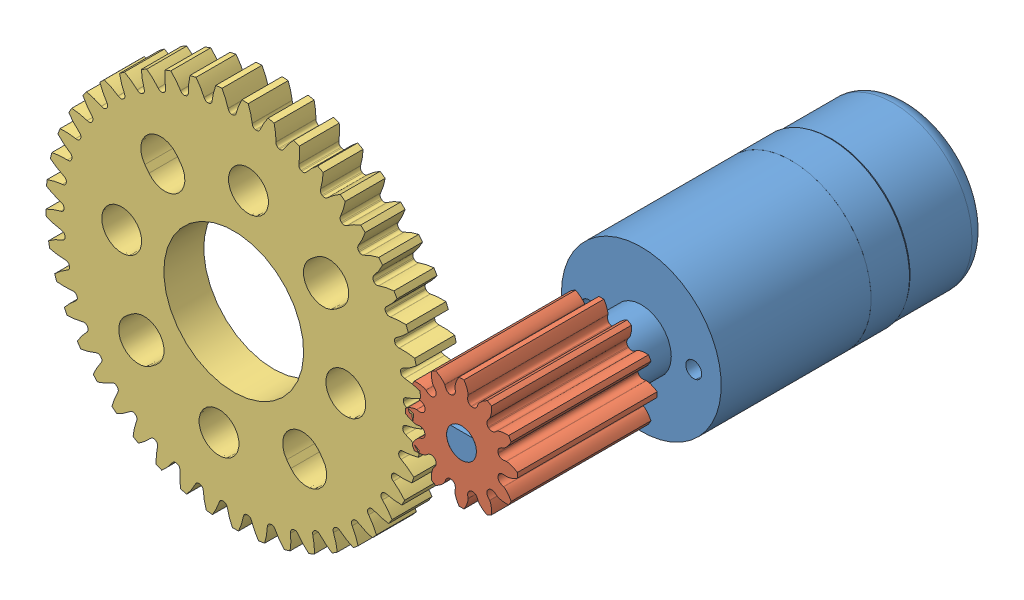
SolidWorks assembly drive, configuration Default. Lengths in mm.
Overall size (51.94 42.17 45.2).
3 component instances, 3 part files, 7 mates.
Components (placement in the parent):
- repeatdriveminimk3-1: repeatdriveminimk3 [Default] at origin size (16.11 16.11 45.2)
- gear-12t-3mm-1: gear-12t-3mm [Default] at (0 0 27) size (11.2 11.2 14)
- gear-45t-1: gear-45t [Default] at (-22.8 0 29) x (-0.991496 0.130138 0) z (0 0 1) size (37.6 37.6 4)
Mates (geometry in assembly coordinates):
- Coincident1: coincident anti-aligned: plane of repeatdriveminimk3-1 through (0 0 19) normal (0 0 1); plane of gear-12t-3mm-1 through (-0.6365 4.0099 19) normal (0 0 -1)
- Coincident2: coincident anti-aligned: line of repeatdriveminimk3-1 through (0 0 40) axis (0 0 -1); line of gear-12t-3mm-1 through (0 0 19) axis (0 0 1)
- Coincident5: coincident: line of gear-12t-3mm-1 through (0 0 19) axis (0 0 1)
- Coincident6: coincident: line of gear-45t-1 through (-22.8 0 29) axis (0 0 1)
- Coincident7: coincident aligned: plane of gear-12t-3mm-1 through (-0.4427 5.2615 33) normal (0 0 1); plane of gear-45t-1 through (-24.7144 -18.297 33) normal (0 0 1)
- Distance1: distance = 22.8 mm: line of gear-45t-1 through (-22.8 0 29) axis (0 0 1); line of repeatdriveminimk3-1 through (0 0 40) axis (0 0 -1)
- Coincident9: coordinate: point of repeatdriveminimk3-1
